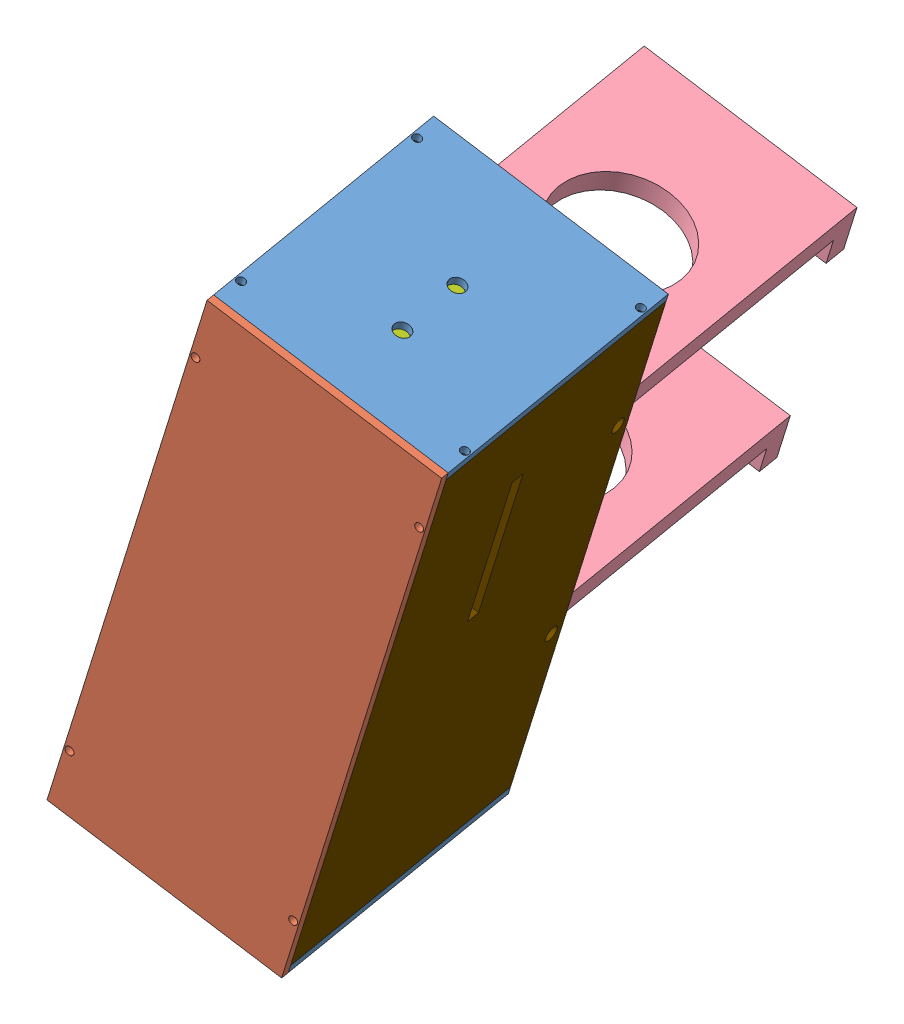
SolidWorks assembly 热裱模组, configuration Default. Lengths in mm.
Overall size (160.08 237.18 221.51).
50 component instances, 20 part files, 71 mates.
Components (placement in the parent):
- R001-1: R001 [默认] at (-91.903 49.6215 5.5245) x (0.943808 -0.302454 -0.13322) z (0.122373 -0.054624 0.99098) size (78 33 70)
- R002-1: R002 [默认] at (-11.4461 127.2113 61.5861) x (0.943808 -0.302454 -0.13322) z (-0.307003 -0.951598 -0.014543) size (15 28 97.4)
- R003-1: R003 [默认] at (-29.6143 -9.0839 -5.4033) x (0.943808 -0.302454 -0.13322) z (-0.307003 -0.951598 -0.014543) size (78 60 15)
- R005-1: R005 [默认] at (-0.108 85.8468 -11.8871) x (0.943808 -0.302454 -0.13322) z (0.307003 0.951598 0.014543) size (78 119.2 18)
- R007-2: R007 [默认] at (-75.759 40.5754 50.3591) x (-0.943808 0.302454 0.13322) z (0.307003 0.951598 0.014543) size (14 20 4)
- R008-1: R008 [默认] at (-1195.1077 -1041.6703 -5332.6259) x (-0.122373 0.054624 -0.99098) z (0.943808 -0.302454 -0.13322) size (14 8 78)
- 加热管-1: 加热管 [默认] at (-21.71 126.542 50.4416) x (0.929687 -0.303132 0.209269) z (0.307003 0.951598 0.014543) size (14 14 120)
- 加热管-2: 加热管 [默认] at (-24.7693 127.9076 25.6671) x (0.881427 -0.290061 0.372763) z (0.307003 0.951598 0.014543) size (14 14 120)
- 包胶滚轮-1: 包胶滚轮 [默认] at (-39.9794 136.6947 33.0752) x (-0.690277 0.233163 -0.684947) z (-0.307003 -0.951598 -0.014543) size (15 15 132)
- MFL126ZZ-2: MFL126ZZ [默认] at (-70.0656 43.4381 31.65) x (-0.307003 -0.951598 -0.014543) z (0.231089 -0.08936 0.96882) size (23.7 35.7 35.7)
- MFL126ZZ-3: MFL126ZZ [默认] at (-39.6724 137.6463 33.0898) x (0.307003 0.951598 0.014543) z (0.010927 -0.018804 0.999763) size (23.7 35.7 35.7)
- 米思米止动扣环5-1: 米思米止动扣环5 [默认] at (-38.3523 141.7382 33.1523) x (0.871358 -0.287195 0.397812) z (-0.307003 -0.951598 -0.014543) size (11 8.93 0.6)
- 米思米止动扣环5-2: 米思米止动扣环5 [默认] at (-71.3857 39.3463 31.5875) x (0.871358 -0.287195 0.397812) z (-0.307003 -0.951598 -0.014543) size (11 8.93 0.6)
- 米思米止动扣环5-3: 米思米止动扣环5 [默认] at (-36.5167 140.9188 48.017) x (0.871358 -0.287195 0.397812) z (-0.307003 -0.951598 -0.014543) size (11 8.93 0.6)
- MFL126ZZ-4: MFL126ZZ [默认] at (-37.8368 136.8269 47.9545) x (0.307003 0.951598 0.014543) z (0.010927 -0.018804 0.999763) size (23.7 35.7 35.7)
- MFL126ZZ-5: MFL126ZZ [默认] at (-68.23 42.6188 46.5147) x (-0.307003 -0.951598 -0.014543) z (0.231089 -0.08936 0.96882) size (23.7 35.7 35.7)
- 米思米止动扣环5-4: 米思米止动扣环5 [默认] at (-69.5501 38.5269 46.4522) x (0.871358 -0.287195 0.397812) z (-0.307003 -0.951598 -0.014543) size (11 8.93 0.6)
- 包胶滚轮-2: 包胶滚轮 [默认] at (-38.1438 135.8753 47.9399) x (-0.690277 0.233163 -0.684947) z (-0.307003 -0.951598 -0.014543) size (15 15 132)
- R006-2: R006 [默认] at (-32.8768 119.6041 2.093) x (0.943808 -0.302454 -0.13322) z (0.122373 -0.054624 0.99098) size (10 10 11.4)
- R002-2: R002 [默认] at (-15.0357 128.8861 32.3531) x (0.943808 -0.302454 -0.13322) z (-0.307003 -0.951598 -0.014543) size (15 28 97.4)
- R006-3: R006 [默认] at (-45.9684 41.7989 10.9247) x (-0.943808 0.302454 0.13322) z (-0.122373 0.054624 -0.99098) size (10 10 11.4)
- R004-2: R004 [默认] at (-56.1679 160.3874 7.2172) x (0.307003 0.951598 0.014543) z (-0.122373 0.054624 -0.99098) size (170 78 5)
- 镜向R001-3: 镜向R001 [默认] at (-60.7729 146.1135 6.9991) x (0.943808 -0.302454 -0.13322) z (-0.122373 0.054624 -0.99098) size (78 33 70)
- R007-3: R007 [默认] at (-29.5736 138.5426 50.056) x (0.943808 -0.302454 -0.13322) z (-0.307003 -0.951598 -0.014543) size (14 20 4)
- R008-2: R008 [默认] at (-1163.3636 -943.2751 -5331.1222) x (-0.122373 0.054624 -0.99098) z (0.943808 -0.302454 -0.13322) size (14 8 78)
- MFL126ZZ-6: MFL126ZZ [默认] at (-1.92 125.5481 27.761) x (0.307003 0.951598 0.014543) z (0.010927 -0.018804 0.999763) size (23.7 35.7 35.7)
- 米思米止动扣环5-5: 米思米止动扣环5 [默认] at (-0.5999 129.64 27.8235) x (0.871358 -0.287195 0.397812) z (-0.307003 -0.951598 -0.014543) size (11 8.93 0.6)
- MFL126ZZ-7: MFL126ZZ [默认] at (-0.0844 124.7288 42.6257) x (0.307003 0.951598 0.014543) z (0.010927 -0.018804 0.999763) size (23.7 35.7 35.7)
- 米思米止动扣环5-6: 米思米止动扣环5 [默认] at (1.2357 128.8206 42.6882) x (0.871358 -0.287195 0.397812) z (-0.307003 -0.951598 -0.014543) size (11 8.93 0.6)
- R007-4: R007 [默认] at (8.1788 126.4444 44.7272) x (0.943808 -0.302454 -0.13322) z (-0.307003 -0.951598 -0.014543) size (14 20 4)
- R007-5: R007 [默认] at (-38.0066 28.4772 45.0303) x (-0.943808 0.302454 0.13322) z (0.307003 0.951598 0.014543) size (14 20 4)
- MFL126ZZ-8: MFL126ZZ [默认] at (-30.4777 30.5206 41.1859) x (-0.307003 -0.951598 -0.014543) z (0.231089 -0.08936 0.96882) size (23.7 35.7 35.7)
- MFL126ZZ-9: MFL126ZZ [默认] at (-32.3133 31.34 26.3212) x (-0.307003 -0.951598 -0.014543) z (0.231089 -0.08936 0.96882) size (23.7 35.7 35.7)
- 米思米止动扣环5-7: 米思米止动扣环5 [默认] at (-31.7978 26.4288 41.1234) x (0.871358 -0.287195 0.397812) z (-0.307003 -0.951598 -0.014543) size (11 8.93 0.6)
- 米思米止动扣环5-8: 米思米止动扣环5 [默认] at (-33.6334 27.2481 26.2587) x (0.871358 -0.287195 0.397812) z (-0.307003 -0.951598 -0.014543) size (11 8.93 0.6)
- 包胶滚轮-3: 包胶滚轮 [默认] at (-2.227 124.5965 27.7464) x (-0.690277 0.233163 -0.684947) z (-0.307003 -0.951598 -0.014543) size (15 15 132)
- 包胶滚轮-4: 包胶滚轮 [默认] at (-0.3914 123.7772 42.6111) x (-0.690277 0.233163 -0.684947) z (-0.307003 -0.951598 -0.014543) size (15 15 132)
- 1模15齿齿轮-1: 1模15齿齿轮 [默认] at (-77.3109 20.9804 31.3068) x (-0.948599 0.307198 -0.076084) z (0.307003 0.951598 0.014543) size (17 17 18)
- 金顺来JGB37-520电机-12-66-2: 金顺来JGB37-520电机-12-66 [默认] at (-62.8609 -0.5111 32.3439) x (-0.943808 0.302454 0.13322) z (-0.307003 -0.951598 -0.014543) size (37 37 68.2)
- 1模25齿齿轮-1: 1模25齿齿轮 [默认] at (-55.7355 24.6128 25.7852) x (0.951455 -0.306532 -0.027794) z (-0.307003 -0.951598 -0.014543) size (27 27 18)
- 1模15齿齿轮-2: 1模15齿齿轮 [默认] at (-75.4753 20.1611 46.1715) x (-0.948599 0.307198 -0.076084) z (0.307003 0.951598 0.014543) size (17 17 18)
- 1模15齿齿轮-3: 1模15齿齿轮 [默认] at (-39.5586 8.8823 25.978) x (-0.948599 0.307198 -0.076084) z (0.307003 0.951598 0.014543) size (17 17 18)
- 1模15齿齿轮-4: 1模15齿齿轮 [默认] at (-37.723 8.0629 40.8427) x (-0.948599 0.307198 -0.076084) z (0.307003 0.951598 0.014543) size (17 17 18)
- 隔热板-1: 隔热板 [默认] at (-101.6622 22.8428 -2.8193) x (0.943808 -0.302454 -0.13322) z (0.122373 -0.054624 0.99098) size (78 100 3)
- R005-2: R005 [默认] at (-27.7382 0.203 -13.1959) x (0.943808 -0.302454 -0.13322) z (0.307003 0.951598 0.014543) size (78 119.2 18)
- 隔热板1-1: 隔热板1 [默认] at (-50.1532 157.2273 87.0285) x (-0.307003 -0.951598 -0.014543) z (0.943808 -0.302454 -0.13322) size (210 100 4)
- 隔热板1-2: 隔热板1 [默认] at (27.239 132.4261 76.1045) x (-0.307003 -0.951598 -0.014543) z (0.943808 -0.302454 -0.13322) size (210 100 4)
- 隔热板2-1: 隔热板2 [默认] at (-48.2656 156.6224 86.7621) x (0.943808 -0.302454 -0.13322) z (0.307003 0.951598 0.014543) size (86 100 3)
- 隔热板2-2: 隔热板2 [默认] at (-113.6572 -46.0679 83.6645) x (0.943808 -0.302454 -0.13322) z (0.307003 0.951598 0.014543) size (86 100 3)
- 隔热板3-1: 隔热板3 [默认] at (-115.5448 -45.463 83.9309) x (0.943808 -0.302454 -0.13322) z (0.122373 -0.054624 0.99098) size (86 216 3)
Mates (geometry in assembly coordinates):
- 同心2: concentric anti-aligned: cylinder of R001-1 through (-48.542 43.3723 49.1706) axis (-0.307003 -0.951598 -0.014543) radius 7; cylinder of 加热管-1 through (-53.0242 29.479 48.9582) axis (0.307003 0.951598 0.014543) radius 7
- 同心3: concentric anti-aligned: cylinder of R001-1 through (-51.6013 44.738 24.3961) axis (-0.307003 -0.951598 -0.014543) radius 7; cylinder of 加热管-2 through (-56.0836 30.8446 24.1838) axis (0.307003 0.951598 0.014543) radius 7
- 重合6: coincident aligned: plane of 加热管-1 through (-53.0242 29.479 48.9582) normal (-0.307003 -0.951598 -0.014543); plane of 加热管-2 through (-56.0836 30.8446 24.1838) normal (-0.307003 -0.951598 -0.014543)
- 同心6: concentric aligned: cylinder of R001-1 through (-67.978 49.909 31.7489) axis (-0.307003 -0.951598 -0.014543) radius 6; cylinder of MFL126ZZ-2 through (-70.1117 43.2954 31.6479) axis (-0.307003 -0.951598 -0.014543) radius 3
- 重合9: coincident anti-aligned: plane of R001-1 through (-83.9508 43.8946 74.864) normal (-0.307003 -0.951598 -0.014543); plane of MFL126ZZ-2 through (-78.9916 43.0316 26.6386) normal (0.307003 0.951598 0.014543)
- 重合10: coincident anti-aligned: plane of 包胶滚轮-1 through (-70.0656 43.4381 31.65) normal (-0.307003 -0.951598 -0.014543); plane of MFL126ZZ-2 through (-74.5806 44.9379 28.8281) normal (0.307003 0.951598 0.014543)
- 同心7: concentric anti-aligned: cylinder of 包胶滚轮-1 through (-36.6023 147.1623 33.2352) axis (-0.307003 -0.951598 -0.014543) radius 3; cylinder of MFL126ZZ-3 through (-39.6263 137.789 33.092) axis (0.307003 0.951598 0.014543) radius 3
- 同心9: concentric anti-aligned: cylinder of 包胶滚轮-1 through (-38.2295 142.1188 33.1581) axis (-0.307003 -0.951598 -0.014543) radius 2.5; cylinder of 米思米止动扣环5-1 through (-38.4444 141.4527 33.1479) axis (0.307003 0.951598 0.014543) radius 2.5
- 重合12: coincident anti-aligned: plane of 包胶滚轮-1 through (-38.4444 141.4527 33.1479) normal (0.307003 0.951598 0.014543); plane of 米思米止动扣环5-1 through (-41.9612 142.67 27.7385) normal (-0.307003 -0.951598 -0.014543)
- 同心10: concentric aligned: cylinder of 包胶滚轮-1 through (-71.5085 38.9656 31.5817) axis (0.307003 0.951598 0.014543) radius 2.5; cylinder of 米思米止动扣环5-2 through (-71.4778 39.0608 31.5832) axis (0.307003 0.951598 0.014543) radius 2.5
- 重合13: coincident anti-aligned: plane of MFL126ZZ-2 through (-76.0566 41.0405 39.961) normal (-0.307003 -0.951598 -0.014543); plane of 米思米止动扣环5-2 through (-65.1106 37.652 30.6109) normal (0.307003 0.951598 0.014543)
- 重合14: coincident anti-aligned: plane of R001-1 through (-83.9508 43.8946 74.864) normal (-0.307003 -0.951598 -0.014543); plane of R007-2 through (-75.452 41.527 50.3737) normal (0.307003 0.951598 0.014543)
- 平行3: parallel aligned: plane of R001-1 through (-83.3368 45.7978 74.893) normal (0.122373 -0.054624 0.99098); plane of R007-2 through (-58.8702 39.0549 68.3718) normal (0.122373 -0.054624 0.99098)
- 同心11: concentric aligned: cylinder of R007-2 through (-68.2914 42.4284 46.5118) axis (-0.307003 -0.951598 -0.014543) radius 6; cylinder of MFL126ZZ-5 through (-69.1664 39.7164 46.4704) axis (-0.307003 -0.951598 -0.014543) radius 6
- 同心12: concentric anti-aligned: cylinder of R001-1 through (-76.1794 51.9656 70.3128) axis (-0.307003 -0.951598 -0.014543) radius 2.5; cylinder of R008-1 through (-80.1704 39.5948 70.1237) axis (0.307003 0.951598 0.014543) radius 2.5
- 同心13: concentric anti-aligned: cylinder of R001-1 through (-12.9442 31.7012 61.387) axis (-0.307003 -0.951598 -0.014543) radius 2.5; cylinder of R008-1 through (-16.9352 19.3304 61.198) axis (0.307003 0.951598 0.014543) radius 2.5
- 重合16: coincident anti-aligned: plane of R001-1 through (-83.3368 45.7978 74.893) normal (0.307003 0.951598 0.014543); plane of R008-1 through (-9.7198 22.2064 64.5019) normal (-0.307003 -0.951598 -0.014543)
- 同心14: concentric aligned: cylinder of R001-1 through (-41.6377 44.6749 72.6082) axis (-0.122373 0.054624 -0.99098) radius 2.25; cylinder of R002-1 through (-33.6345 41.1025 137.4183) axis (-0.122373 0.054624 -0.99098) radius 2.25
- 重合19: coincident anti-aligned: plane of R001-1 through (-84.2057 46.1856 67.8571) normal (-0.122373 0.054624 -0.99098); plane of R002-1 through (-53.4052 38.3627 63.6224) normal (0.122373 -0.054624 0.99098)
- 同心17: concentric anti-aligned: cylinder of R006-2 through (-25.2277 122.2271 12.7968) axis (0.122373 -0.054624 0.99098) radius 1.65; cylinder of R002-2 through (-13.3085 116.9067 109.3183) axis (-0.122373 0.054624 -0.99098) radius 2.25
- 平行7: parallel aligned: plane of R002-1 through (-13.0851 127.7365 61.8174) normal (0.307003 0.951598 0.014543); plane of R002-2 through (-16.6747 129.4113 32.5845) normal (0.307003 0.951598 0.014543)
- 重合26: coincident anti-aligned: plane of R006-2 through (-31.4818 118.9814 13.3902) normal (0.122373 -0.054624 0.99098); plane of R002-2 through (-49.0565 37.8326 11.0874) normal (-0.122373 0.054624 -0.99098)
- 同心19: concentric aligned: cylinder of R006-2 through (-25.2277 122.2271 12.7968) axis (0.122373 -0.054624 0.99098) radius 1.65; cylinder of R004-2 through (-27.2346 123.123 -3.4552) axis (0.122373 -0.054624 0.99098) radius 2.25
- 同心20: concentric anti-aligned: cylinder of R006-3 through (-50.5475 48.6919 0.3663) axis (-0.122373 0.054624 -0.99098) radius 1.65; cylinder of R004-2 through (-51.1593 48.965 -4.5886) axis (0.122373 -0.054624 0.99098) radius 2.25
- 平行9: parallel aligned: plane of R006-2 through (-28.4117 128.4974 13.5356) normal (0.307003 0.951598 0.014543); plane of R004-2 through (-56.7797 160.6606 2.2623) normal (0.307003 0.951598 0.014543)
- 重合31: coincident anti-aligned: plane of R006-3 through (-47.3634 42.4216 -0.3725) normal (-0.122373 0.054624 -0.99098); plane of R004-2 through (-56.1679 160.3874 7.2172) normal (0.122373 -0.054624 0.99098)
- 平行10: parallel aligned: plane of R006-3 through (-56.8015 45.4461 0.9597) normal (-0.943808 0.302454 0.13322); plane of R004-2 through (-108.9702 -1.111 -0.2099) normal (-0.943808 0.302454 0.13322)
- 重合33: coincident aligned: plane of R004-2 through (-56.7797 160.6606 2.2623) normal (0.307003 0.951598 0.014543); plane of 镜向R001-3 through (17.4492 136.7961 -3.1739) normal (0.307003 0.951598 0.014543)
- 重合34: coincident anti-aligned: plane of R006-2 through (-32.8768 119.6041 2.093) normal (-0.122373 0.054624 -0.99098); plane of R004-2 through (-56.1679 160.3874 7.2172) normal (0.122373 -0.054624 0.99098)
- 平行11: parallel aligned: plane of R002-2 through (-44.9377 36.2005 30.9367) normal (0.943808 -0.302454 -0.13322); plane of 镜向R001-3 through (21.4103 118.6984 65.9765) normal (0.943808 -0.302454 -0.13322)
- 重合36: coincident: plane of R004-2 through (-108.9702 -1.111 -0.2099) normal (-0.943808 0.302454 0.13322); line of 镜向R001-3 through (-59.688 148.6084 9.0209) axis (0.307003 0.951598 0.014543)
- 重合37: coincident anti-aligned: plane of R001-1 through (-91.903 49.6215 5.5245) normal (-0.122373 0.054624 -0.99098); plane of R004-2 through (-56.1679 160.3874 7.2172) normal (0.122373 -0.054624 0.99098)
- 同心22: concentric anti-aligned: cylinder of 包胶滚轮-1 through (-77.1267 21.5514 31.3156) axis (0.307003 0.951598 0.014543) radius 3; cylinder of MFL126ZZ-2 through (-70.1117 43.2954 31.6479) axis (-0.307003 -0.951598 -0.014543) radius 3
- 重合40: coincident aligned: plane of R003-1 through (-103.357 12.9307 7.6779) normal (-0.943808 0.302454 0.13322); plane of R004-2 through (-108.9702 -1.111 -0.2099) normal (-0.943808 0.302454 0.13322)
- 重合41: coincident anti-aligned: plane of R003-1 through (-103.6919 13.0801 4.966) normal (-0.122373 0.054624 -0.99098); plane of R004-2 through (-56.1679 160.3874 7.2172) normal (0.122373 -0.054624 0.99098)
- 对称2: symmetric aligned: plane of R003-1 through (-93.8765 4.7161 18.4294) normal (-0.307003 -0.951598 -0.014543); plane of R003-1 through (-95.565 -0.5176 18.3495) normal (0.307003 0.951598 0.014543); plane of assembly through (-8.2321 -25.5165 -0.39) normal (-0.307003 -0.951598 -0.014543)
- 重合42: coincident anti-aligned: plane of MFL126ZZ-4 through (-30.3807 137.8904 41.0098) normal (-0.307003 -0.951598 -0.014543); plane of 镜向R001-3 through (-51.5928 144.193 76.3968) normal (0.307003 0.951598 0.014543)
- 重合43: coincident anti-aligned: plane of 镜向R001-3 through (-42.3933 130.7451 74.5195) normal (0.943808 -0.302454 -0.13322); plane of R007-3 through (-42.7641 139.6197 51.7442) normal (-0.943808 0.302454 0.13322)
- 重合44: coincident anti-aligned: plane of 镜向R001-3 through (-52.2068 142.2898 76.3677) normal (-0.307003 -0.951598 -0.014543); plane of R007-3 through (-43.7079 139.9221 51.8774) normal (0.307003 0.951598 0.014543)
- 同心23: concentric aligned: cylinder of MFL126ZZ-4 through (-36.9004 139.7293 47.9988) axis (0.307003 0.951598 0.014543) radius 6; cylinder of R007-3 through (-37.7754 137.0172 47.9574) axis (0.307003 0.951598 0.014543) radius 6
- 同心24: concentric aligned: cylinder of 镜向R001-3 through (-49.9613 133.232 71.5547) axis (0.307003 0.951598 0.014543) radius 2.5; cylinder of R008-2 through (-48.4263 137.99 71.6274) axis (0.307003 0.951598 0.014543) radius 2.5
- 同心25: concentric aligned: cylinder of 镜向R001-3 through (13.2738 112.9676 62.629) axis (0.307003 0.951598 0.014543) radius 2.5; cylinder of R008-2 through (14.8088 117.7256 62.7017) axis (0.307003 0.951598 0.014543) radius 2.5
- 重合45: coincident anti-aligned: plane of 镜向R001-3 through (-51.5928 144.193 76.3968) normal (0.307003 0.951598 0.014543); plane of R008-2 through (22.0243 120.6016 66.0056) normal (-0.307003 -0.951598 -0.014543)
- 同心26: concentric aligned: cylinder of 包胶滚轮-1 through (-77.1267 21.5514 31.3156) axis (0.307003 0.951598 0.014543) radius 3; cylinder of 1模15齿齿轮-1 through (-77.3109 20.9804 31.3068) axis (0.307003 0.951598 0.014543) radius 3
- 同心28: concentric anti-aligned: cylinder of R003-1 through (-63.7176 -0.1287 25.4071) axis (0.307003 0.951598 0.014543) radius 6; cylinder of 金顺来JGB37-520电机-12-66-2 through (-61.8755 5.5809 25.4943) axis (-0.307003 -0.951598 -0.014543) radius 6
- 平行13: parallel anti-aligned: plane of R004-2 through (-56.1679 160.3874 7.2172) normal (0.122373 -0.054624 0.99098); plane of 金顺来JGB37-520电机-12-66-2 through (-63.7016 9.8795 23.434) normal (-0.122373 0.054624 -0.99098)
- 重合49: coincident anti-aligned: plane of R003-1 through (-30.0748 -10.5113 -5.4251) normal (-0.307003 -0.951598 -0.014543); plane of 金顺来JGB37-520电机-12-66-2 through (-62.8609 -0.5111 32.3439) normal (0.307003 0.951598 0.014543)
- 同心29: concentric aligned: cylinder of 金顺来JGB37-520电机-12-66-2 through (-57.117 20.3307 25.7198) axis (-0.307003 -0.951598 -0.014543) radius 3; cylinder of 1模25齿齿轮-1 through (-55.7355 24.6128 25.7852) axis (-0.307003 -0.951598 -0.014543) radius 3
- 距离3: distance = 2 mm anti-aligned: plane of 1模25齿齿轮-1 through (-61.2615 7.4841 25.5234) normal (-0.307003 -0.951598 -0.014543); plane of 金顺来JGB37-520电机-12-66-2 through (-61.8755 5.5809 25.4943) normal (0.307003 0.951598 0.014543)
- 重合51: coincident aligned: plane of 1模15齿齿轮-1 through (-77.3109 20.9804 31.3068) normal (-0.307003 -0.951598 -0.014543); plane of 1模25齿齿轮-1 through (-58.8055 15.0969 25.6398) normal (-0.307003 -0.951598 -0.014543)
- 距离4: distance = 10 mm aligned: plane of 加热管-2 through (-19.2433 145.0363 25.9289) normal (0.307003 0.951598 0.014543); plane of 镜向R001-3 through (-51.5928 144.193 76.3968) normal (0.307003 0.951598 0.014543)
- 同心30: concentric aligned: cylinder of R005-1 through (-8.318 92.6777 -10.4967) axis (0.122373 -0.054624 0.99098) radius 2.1; cylinder of R004-2 through (-7.9509 92.5138 -7.5238) axis (0.122373 -0.054624 0.99098) radius 2.75
- 同心31: concentric anti-aligned: cylinder of R005-1 through (-63.0589 110.22 -2.7699) axis (0.122373 -0.054624 0.99098) radius 2.1; circle of R004-2
- 重合54: coincident aligned: plane of R004-2 through (-108.9702 -1.111 -0.2099) normal (-0.943808 0.302454 0.13322); plane of 隔热板-1 through (-101.2951 22.6789 0.1536) normal (-0.943808 0.302454 0.13322)
- 平行14: parallel aligned: plane of R004-2 through (-56.7797 160.6606 2.2623) normal (0.307003 0.951598 0.014543); plane of 隔热板-1 through (-70.5949 117.8387 1.6079) normal (0.307003 0.951598 0.014543)
- 同心32: concentric aligned: cylinder of R004-2 through (-62.6918 110.0561 0.203) axis (0.122373 -0.054624 0.99098) radius 2.75; cylinder of 隔热板-1 through (-63.9155 110.6024 -9.7068) axis (0.122373 -0.054624 0.99098) radius 2.75
- 重合56: coincident anti-aligned: plane of R004-2 through (-56.7797 160.6606 2.2623) normal (-0.122373 0.054624 -0.99098); plane of 隔热板-1 through (-101.2951 22.6789 0.1536) normal (0.122373 -0.054624 0.99098)
- 重合57: coincident anti-aligned: plane of R005-1 through (-71.269 117.0509 -1.3796) normal (0.122373 -0.054624 0.99098); plane of 隔热板-1 through (-101.6622 22.8428 -2.8193) normal (-0.122373 0.054624 -0.99098)
- 平行15: parallel anti-aligned: plane of R005-1 through (-85.9085 123.5857 -119.9305) normal (-0.943808 0.302454 0.13322); plane of 隔热板1-1 through (-46.378 156.0175 86.4956) normal (0.943808 -0.302454 -0.13322)
- 重合59: coincident anti-aligned: plane of R005-1 through (-85.9085 123.5857 -119.9305) normal (-0.943808 0.302454 0.13322); plane of 隔热板1-1 through (-46.378 156.0175 86.4956) normal (0.943808 -0.302454 -0.13322)
- 重合60: coincident aligned: plane of R004-2 through (-56.7797 160.6606 2.2623) normal (0.307003 0.951598 0.014543); plane of 隔热板1-1 through (-46.378 156.0175 86.4956) normal (0.307003 0.951598 0.014543)
- 距离5: distance = 15 mm aligned: plane of 隔热板1-1 through (-58.6153 161.4799 -12.6024) normal (-0.122373 0.054624 -0.99098); plane of R004-2 through (-56.7797 160.6606 2.2623) normal (-0.122373 0.054624 -0.99098)
- 重合64: coincident anti-aligned: plane of 隔热板1-2 through (31.0143 131.2163 75.5716) normal (0.307003 0.951598 0.014543); plane of 隔热板2-1 through (-48.2656 156.6224 86.7621) normal (-0.307003 -0.951598 -0.014543)
- 重合65: coincident aligned: plane of 隔热板1-2 through (31.0143 131.2163 75.5716) normal (0.943808 -0.302454 -0.13322); plane of 隔热板2-1 through (31.9353 134.0711 75.6152) normal (0.943808 -0.302454 -0.13322)
- 重合66: coincident aligned: plane of 隔热板1-2 through (31.0143 131.2163 75.5716) normal (0.122373 -0.054624 0.99098); plane of 隔热板2-1 through (-47.3446 159.4772 86.8057) normal (0.122373 -0.054624 0.99098)
- 重合67: coincident aligned: plane of 隔热板1-1 through (-46.378 156.0175 86.4956) normal (0.122373 -0.054624 0.99098); plane of 隔热板2-2 through (-112.7362 -43.2131 83.7081) normal (0.122373 -0.054624 0.99098)
- 重合68: coincident aligned: plane of 隔热板1-1 through (-50.1532 157.2273 87.0285) normal (-0.943808 0.302454 0.13322); plane of 隔热板2-2 through (-115.5448 -45.463 83.9309) normal (-0.943808 0.302454 0.13322)
- 重合69: coincident anti-aligned: plane of 隔热板1-1 through (-114.6238 -42.6082 83.9745) normal (-0.307003 -0.951598 -0.014543); plane of 隔热板2-2 through (-112.7362 -43.2131 83.7081) normal (0.307003 0.951598 0.014543)
- 重合70: coincident anti-aligned: plane of 隔热板1-1 through (-46.378 156.0175 86.4956) normal (0.122373 -0.054624 0.99098); plane of 隔热板3-1 through (-115.5448 -45.463 83.9309) normal (-0.122373 0.054624 -0.99098)
- 重合71: coincident aligned: plane of 隔热板2-2 through (-113.6572 -46.0679 83.6645) normal (-0.307003 -0.951598 -0.014543); plane of 隔热板3-1 through (-115.1777 -45.6269 86.9038) normal (-0.307003 -0.951598 -0.014543)
- 重合72: coincident aligned: plane of 隔热板1-2 through (31.0143 131.2163 75.5716) normal (0.943808 -0.302454 -0.13322); plane of 隔热板3-1 through (-34.0102 -71.6379 75.4469) normal (0.943808 -0.302454 -0.13322)
